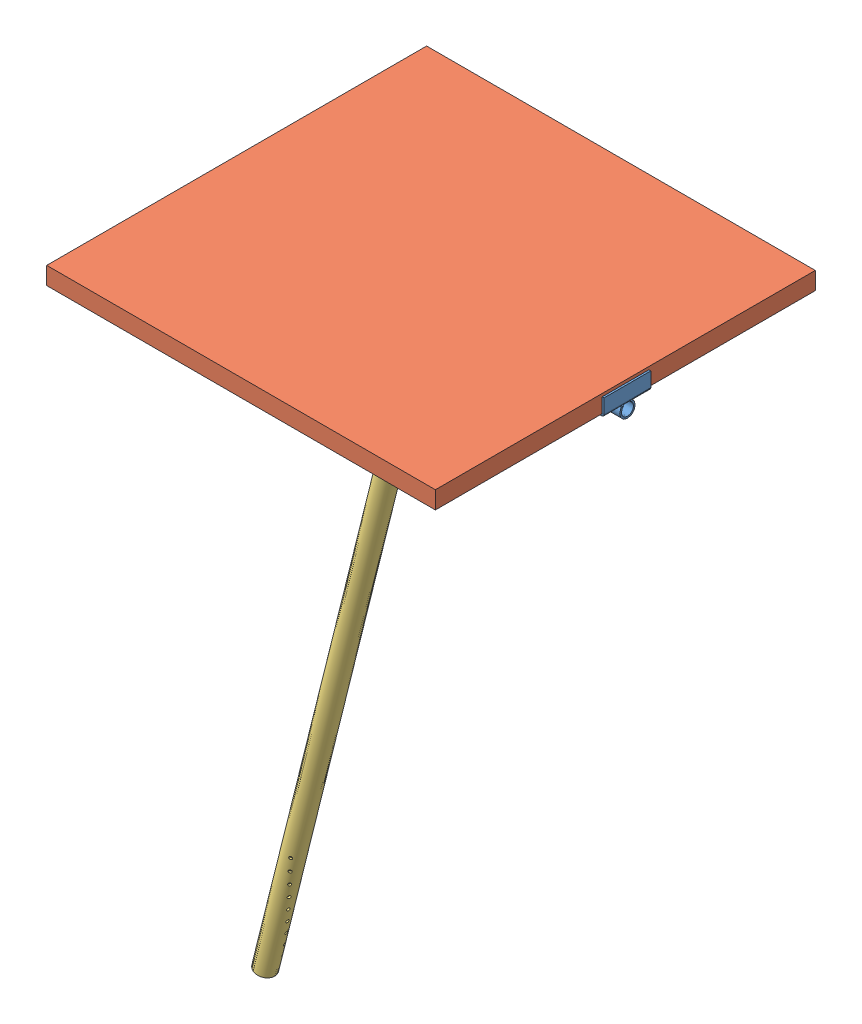
SolidWorks assembly Assem1, configuration Default. Lengths in mm.
Overall size (672.2 1184.86 650).
3 component instances, 3 part files, 4 mates.
Components (placement in the parent):
- Across Mount-1: Across Mount [Default<As Machined>] at (170.9825 404.5818 538.7635) size (672.2 124.49 80)
- Panel-1: Panel [Default] at (-161.5175 416.0918 213.7635) x (1 0 0) z (0 0 -1) size (665 30 650)
- Stand-1: Stand [Default] at (129.2068 237.0287 538.7635) x (0.476491 -0.118803 0.871116) z (0.84524 -0.210742 -0.491078) size (33.4 1000 33.4)
Mates (geometry in assembly coordinates):
- Concentric4: concentric aligned: cylinder of Across Mount-1 through (136.8279 267.5951 538.7635) axis (0.241922 0.970296 0) radius 17.52; cylinder of Stand-1 through (-112.7151 -733.267 538.7635) axis (0.241922 0.970296 0) radius 16.7
- Width1: width anti-aligned: plane of Panel-1 through (-161.5175 446.0918 213.7635) normal (0 0 -1); plane of Panel-1 through (-161.5175 446.0918 863.7635) normal (0 0 1); plane of Across Mount-1 through (-161.4175 412.9168 578.7635) normal (0 0 1); plane of Across Mount-1 through (-161.4175 416.5918 498.7635) normal (0 0 -1)
- Coincident1: coincident anti-aligned: plane of Panel-1 through (-161.5175 416.0918 213.7635) normal (0 -1 0); plane of Across Mount-1 through (-136.5175 416.0918 578.7635) normal (0 1 0)
- Concentric6: concentric anti-aligned: cylinder of Across Mount-1 through (-148.0175 416.0918 514.7635) axis (0 1 0) radius 2.5273; cylinder of Panel-1 through (-148.0175 416.0918 514.7635) axis (0 -1 0) radius 2.5273
